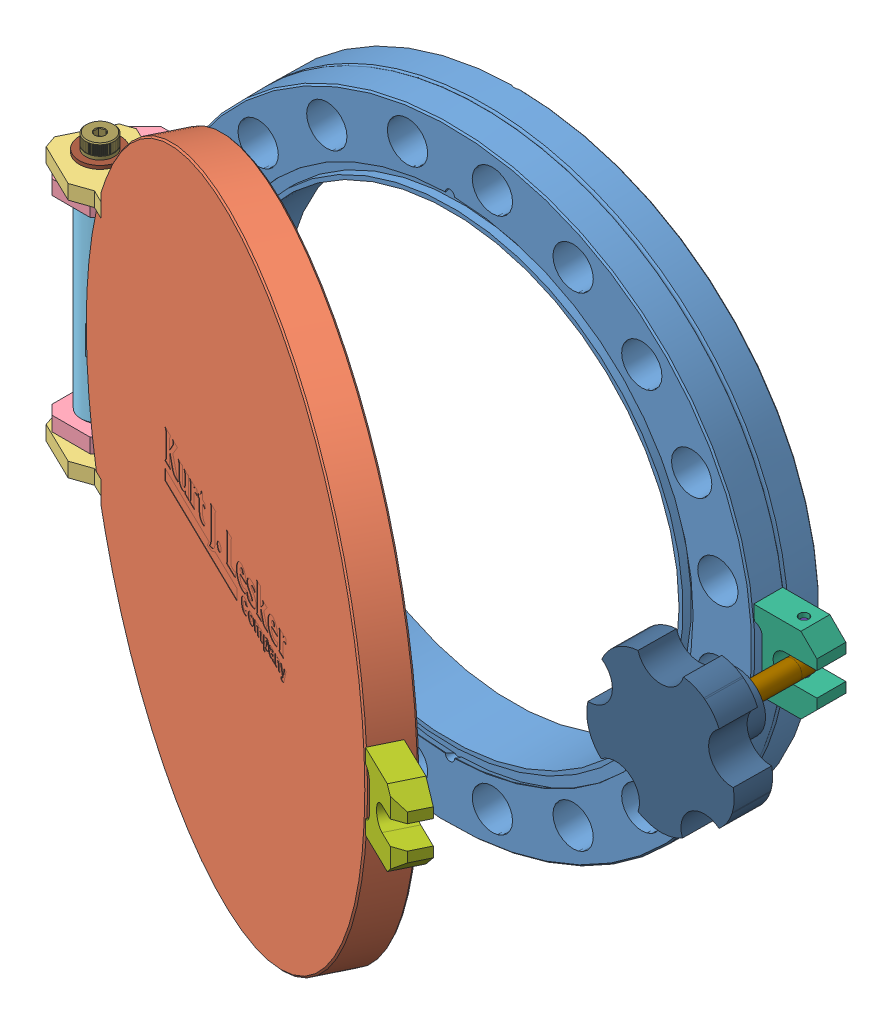
SolidWorks assembly ds-ll0800, configuration Default. Lengths in mm.
18 component instances, 12 part files, 35 mates.
Components (placement in the parent):
- p0018250-1: p0018250 [Default] at origin size (202.44 202.44 22.5)
- p0018251-1: p0018251 [Default] at (-7.8986 0 71.3575) x (0.899135 0 0.437671) z (-0.437671 0 0.899135) size (202.44 202.44 14.11)
- p0018240-1: p0018240 [Default] at (-104.8871 42.545 32.0564) x (-0.437671 0 0.899135) z (-0.899135 0 -0.437671) size (22.5 4.83 28.57)
- p0018240-2: p0018240 [Default] at (-104.8871 -42.545 32.0564) x (0.437671 0 -0.899135) z (-0.899135 0 -0.437671) size (22.5 4.83 28.57)
- p0018239-1: p0018239 [Default] at (-105.9942 36.576 22.987) size (25.4 4.83 33.27)
- p0018239-2: p0018239 [Default] at (-105.9942 -31.75 22.987) size (25.4 4.83 33.27)
- U-SETF0.50-L2.50-T10-U10-SC0.75-1: U-SETF0.50-L2.50-T10-U10-SC0.75 [Default] at (-109.1692 -31.75 29.972) x (0 1 0) z (-0.658501 0 -0.75258) size (63.5 12.7 12.7)
- p0018236-1: p0018236 [Default] at (111.125 0 11.9062) x (0 -1 0) z (1 0 0) size (25.4 9.65 21.08)
- p0018235-1: p0018235 [Default] at (90.9212 0 123.6973) x (0 -1 0) z (0.899135 0 0.437671) size (25.4 9.65 21.08)
- .125 dia roll-pin-1: .125 dia roll-pin [Default] at (112.522 11.1125 16.7323) x (-1 0 0) z (0 -1 0) size (3.17 3.17 22.23)
- p0018237-1: p0018237 [Default] at (112.1496 -0.8001 51.0202) x (0 -1 0) z (0.010859 0 -0.999941) size (6.35 6.35 38.1)
- p0018238-1: p0018238 [Default] at (112.2831 -0.8001 38.73) x (-0.9267 0.375666 -0.010064) z (-0.010859 0 0.999941) size (49.16 49.69 25.4)
- P0046803-1: P0046803 [Default] at (-109.1692 38.1635 29.972) x (0.401413 0 0.915897) z (0 1 0) size (13.89 13.89 3.17)
- P0046803-2: P0046803 [Default] at (-109.1692 42.1005 29.972) x (0.555398 0 -0.831585) z (0 -1 0) size (13.89 13.89 3.17)
- P0046803-3: P0046803 [Default] at (-109.1692 -42.1005 29.972) x (1 0 0) z (0 1 0) size (13.89 13.89 3.17)
- P0046803-4: P0046803 [Default] at (-109.1692 -38.1635 29.972) x (1 0 0) z (0 -1 0) size (13.89 13.89 3.17)
- 97345A183-1: 97345A183 [Default] at (-109.1692 -48.4505 29.972) x (0.444033 0 -0.89601) z (0 -1 0) size (9.53 9.53 24.05)
- 97345A183-2: 97345A183 [Default] at (-109.1692 48.4505 29.972) x (-0.997749 0 -0.067066) z (0 1 0) size (9.53 9.53 24.05)
Mates (geometry in assembly coordinates):
- Coincident9: coincident anti-aligned: plane of p0018251-1 through (-150.0706 37.719 157.5242) normal (-0.899135 0 -0.437671); plane of p0018240-1 through (-87.1159 37.719 28.1924) normal (0.899135 0 0.437671)
- Coincident10: coincident aligned: plane of p0018251-1 through (-13.7905 0 83.4617) normal (-0.437671 0 0.899135); plane of p0018240-1 through (-98.9764 158.369 41.9959) normal (-0.437671 0 0.899135)
- Coincident11: coincident: line of p0018251-1 through (-92.5754 37.719 30.7045) axis (-0.437671 0 0.899135); plane of p0018240-1 through (-87.1159 37.719 28.1924) normal (0 -1 0)
- Coincident12: coincident anti-aligned: plane of p0018251-1 through (-150.0706 -37.719 157.5242) normal (-0.899135 0 -0.437671); plane of p0018240-2 through (-96.9654 -37.719 48.4269) normal (0.899135 0 0.437671)
- Coincident13: coincident aligned: plane of p0018251-1 through (-13.7905 0 83.4617) normal (-0.437671 0 0.899135); plane of p0018240-2 through (-98.9764 -158.369 41.9959) normal (-0.437671 0 0.899135)
- Coincident14: coincident: line of p0018251-1 through (-92.5754 -37.719 30.7045) axis (-0.437671 0 0.899135); plane of p0018240-2 through (-96.9654 -37.719 48.4269) normal (0 1 0)
- Concentric3: concentric aligned: cylinder of p0018240-1 through (-109.1692 74.4105 29.972) axis (0 1 0) radius 6.35; cylinder of P0046803-1 through (-109.1692 92.1702 29.972) axis (0 1 0) radius 6.35
- Coincident15: coincident anti-aligned: plane of p0018240-1 through (-87.1159 37.719 28.1924) normal (0 -1 0); plane of P0046803-1 through (-111.7182 37.719 24.1561) normal (0 1 0)
- Concentric4: concentric anti-aligned: cylinder of p0018240-1 through (-109.1692 74.4105 29.972) axis (0 1 0) radius 6.35; cylinder of P0046803-2 through (-109.1692 -11.9062 29.972) axis (0 -1 0) radius 6.35
- Coincident16: coincident anti-aligned: plane of p0018240-1 through (-87.1159 42.545 28.1924) normal (0 1 0); plane of P0046803-2 through (-112.696 42.545 35.2526) normal (0 -1 0)
- Concentric5: concentric anti-aligned: cylinder of P0046803-2 through (-109.1692 -11.9062 29.972) axis (0 -1 0) radius 3.175; cylinder of 97345A183-2 through (-109.1692 24.638 29.972) axis (0 1 0) radius 3.175
- Coincident17: coincident anti-aligned: plane of P0046803-2 through (-113.0275 43.688 35.7489) normal (0 1 0); plane of 97345A183-2 through (-108.8498 43.688 25.2202) normal (0 -1 0)
- Coincident18: coincident anti-aligned: plane of p0018240-2 through (-96.9654 -42.545 48.4269) normal (0 -1 0); plane of P0046803-3 through (-115.5192 -42.545 29.972) normal (0 1 0)
- Concentric6: concentric anti-aligned: cylinder of p0018240-2 through (-109.1692 -74.4105 29.972) axis (0 -1 0) radius 6.35; cylinder of P0046803-3 through (-109.1692 11.9062 29.972) axis (0 1 0) radius 6.35
- Coincident19: coincident anti-aligned: plane of p0018240-2 through (-96.9654 -37.719 48.4269) normal (0 1 0); plane of P0046803-4 through (-115.5192 -37.719 29.972) normal (0 -1 0)
- Concentric7: concentric aligned: cylinder of p0018240-2 through (-109.1692 -74.4105 29.972) axis (0 -1 0) radius 6.35; cylinder of P0046803-4 through (-109.1692 -92.1702 29.972) axis (0 -1 0) radius 6.35
- Concentric8: concentric anti-aligned: cylinder of P0046803-3 through (-109.1692 11.9062 29.972) axis (0 1 0) radius 3.175; cylinder of 97345A183-1 through (-109.1692 -24.638 29.972) axis (0 -1 0) radius 3.175
- Coincident20: coincident anti-aligned: plane of P0046803-3 through (-116.1161 -43.688 29.972) normal (0 -1 0); plane of 97345A183-1 through (-113.4364 -43.688 27.8573) normal (0 1 0)
- Concentric9: concentric anti-aligned: cylinder of U-SETF0.50-L2.50-T10-U10-SC0.75-1 through (-109.1692 0 29.972) axis (0 -1 0) radius 6.35; cylinder of 97345A183-2 through (-109.1692 24.638 29.972) axis (0 1 0) radius 3.175
- Coincident22: coincident anti-aligned: plane of p0018250-1 through (-93.2942 31.75 69.85) normal (-1 0 0); plane of p0018239-1 through (-93.2942 31.75 6.35) normal (1 0 0)
- Coincident23: coincident aligned: plane of p0018250-1 through (0 0 22.352) normal (0 0 1); plane of p0018239-1 through (-99.6442 139.7 22.352) normal (0 0 1)
- Coincident24: coincident anti-aligned: plane of p0018250-1 through (-144.0942 31.75 69.85) normal (0 1 0); plane of p0018239-1 through (-118.6942 31.75 6.35) normal (0 -1 0)
- Coincident25: coincident anti-aligned: plane of p0018250-1 through (-93.2942 -31.75 69.85) normal (-1 0 0); plane of p0018239-2 through (-93.2942 -36.576 6.35) normal (1 0 0)
- Coincident26: coincident anti-aligned: plane of p0018250-1 through (-144.0942 -31.75 69.85) normal (0 -1 0); plane of p0018239-2 through (-118.6942 -31.75 6.35) normal (0 1 0)
- Coincident27: coincident aligned: plane of p0018250-1 through (0 0 22.352) normal (0 0 1); plane of p0018239-2 through (-99.6442 71.374 22.352) normal (0 0 1)
- Concentric10: concentric anti-aligned: cylinder of p0018239-2 through (-109.1692 5.562 29.972) axis (0 1 0) radius 3.2004; cylinder of U-SETF0.50-L2.50-T10-U10-SC0.75-1 through (-109.1692 0 29.972) axis (0 -1 0) radius 6.35
- Coincident28: coincident anti-aligned: plane of p0018239-1 through (-118.6942 36.576 6.35) normal (0 1 0); plane of P0046803-1 through (-111.9578 36.576 23.6094) normal (0 -1 0)
- Coincident29: coincident anti-aligned: plane of p0018239-2 through (-118.6942 -31.75 6.35) normal (0 1 0); plane of U-SETF0.50-L2.50-T10-U10-SC0.75-1 through (-106.9709 -31.75 28.0485) normal (0 -1 0)
- Lock1: lock: unknown of p0018250-1; unknown of p0018236-1
- Coincident32: coincident aligned: plane of p0018251-1 through (-13.7905 0 83.4617) normal (-0.437671 0 0.899135); plane of p0018235-1 through (77.219 12.7 127.7623) normal (-0.437671 0 0.899135)
- Coincident33: coincident aligned: plane of p0018236-1 through (110.998 -3.9624 -89.5667) normal (0 1 0); plane of p0018235-1 through (136.5891 -3.9624 33.0708) normal (0 1 0)
- Tangent3: tangent anti-aligned: cylinder of p0018251-1 through (-13.7905 0 83.4617) axis (-0.437671 0 0.899135) radius 101.219; plane of p0018235-1 through (77.219 12.7 127.7623) normal (-0.899135 0 -0.437671)
- Concentric11: concentric anti-aligned: cylinder of p0018236-1 through (112.522 34.3914 16.7323) axis (0 1 0) radius 1.6129; cylinder of p0018237-1 through (112.522 -39.9441 16.7323) axis (0 -1 0) radius 1.7859
- Tangent4: tangent anti-aligned: plane of p0018236-1 through (110.998 -3.9624 -89.5667) normal (0 1 0); cylinder of p0018237-1 through (112.5634 -0.8001 12.9225) axis (0.010859 0 -0.999941) radius 3.1623
- Concentric12: concentric aligned: cylinder of p0018237-1 through (112.5634 -0.8001 12.9225) axis (0.010859 0 -0.999941) radius 3.175; cylinder of p0018238-1 through (112.2831 -0.8001 38.73) axis (0.010859 0 -0.999941) radius 2.4879
